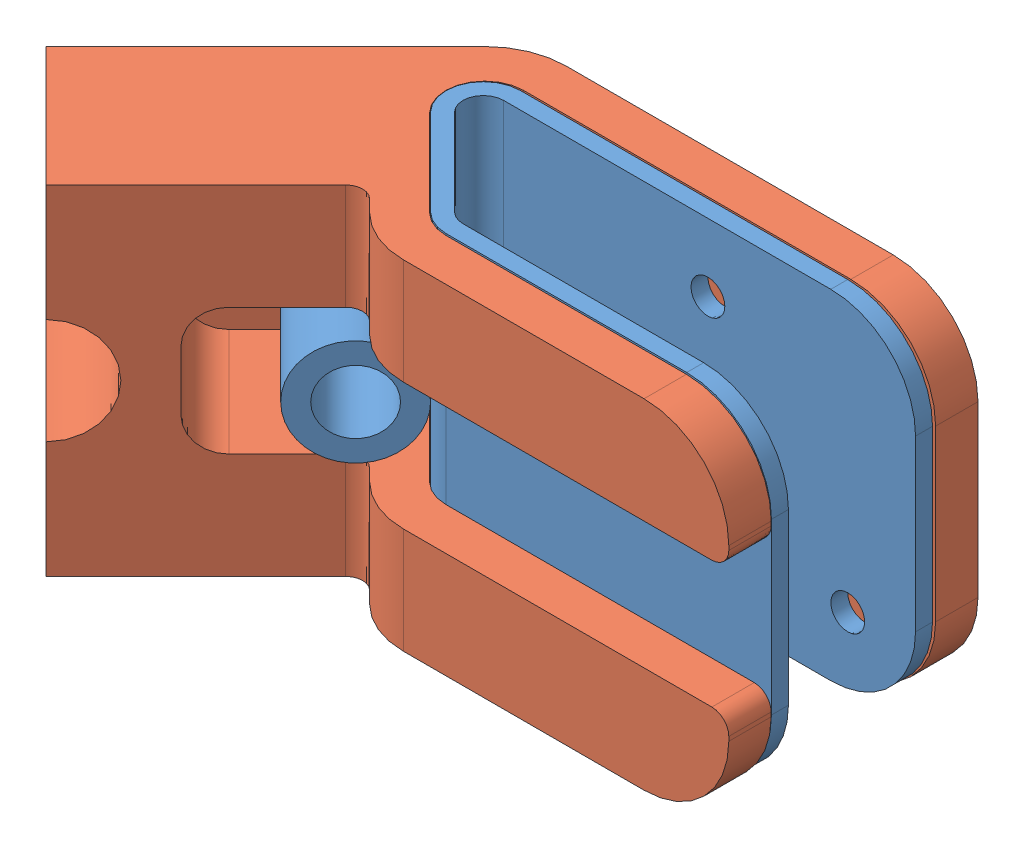
SolidWorks assembly WheelAssy, configuration Default. Lengths in mm.
Overall size (117.01 50.8 141.46).
2 component instances, 2 part files, 2 mates.
Components (placement in the parent):
- Knuckle-1: Knuckle [Default] at origin size (108.46 50.8 141.46)
- MotorMount-1: MotorMount [Default] at (0.212 0 0) x (0 1 0) z (-1 0 0) size (50.8 54.4 103.21)
Mates (geometry in assembly coordinates):
- Coincident1: coincident aligned: plane of Knuckle-1 through (0 0 0) normal (0 1 0); plane of MotorMount-1 through (0.212 0 0) normal (0 1 0)
- Coincident2: coincident anti-aligned: plane of Knuckle-1 through (0 0 0) normal (0 0 1); plane of MotorMount-1 through (0.212 0 0) normal (0 0 -1)
